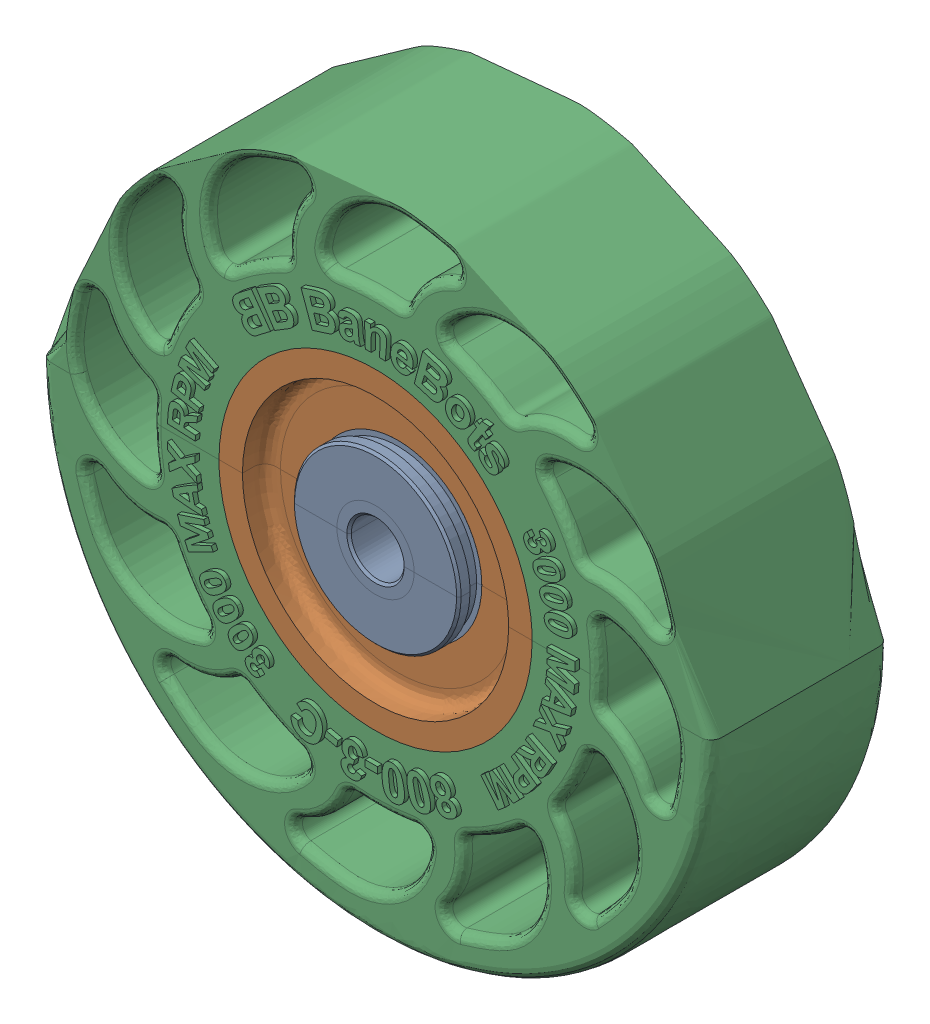
SolidWorks assembly Wheel Assembly, configuration Default. Lengths in mm.
Overall size (76.2 76.2 21.34).
2 component instances, 2 part files, 2 mates.
Components (placement in the parent):
- T81H-RM61-1: T81H-RM61 [Default] at origin size (20.32 20.32 20.32)
- T81P-30-C-1: T81P-30-C [Default] at origin size (76.2 76.2 21.34)
Mates (geometry in assembly coordinates):
- Coincident1: coordinate: point of T81H-RM61-1
- Coincident2: coordinate: unknown of T81P-30-C-1
